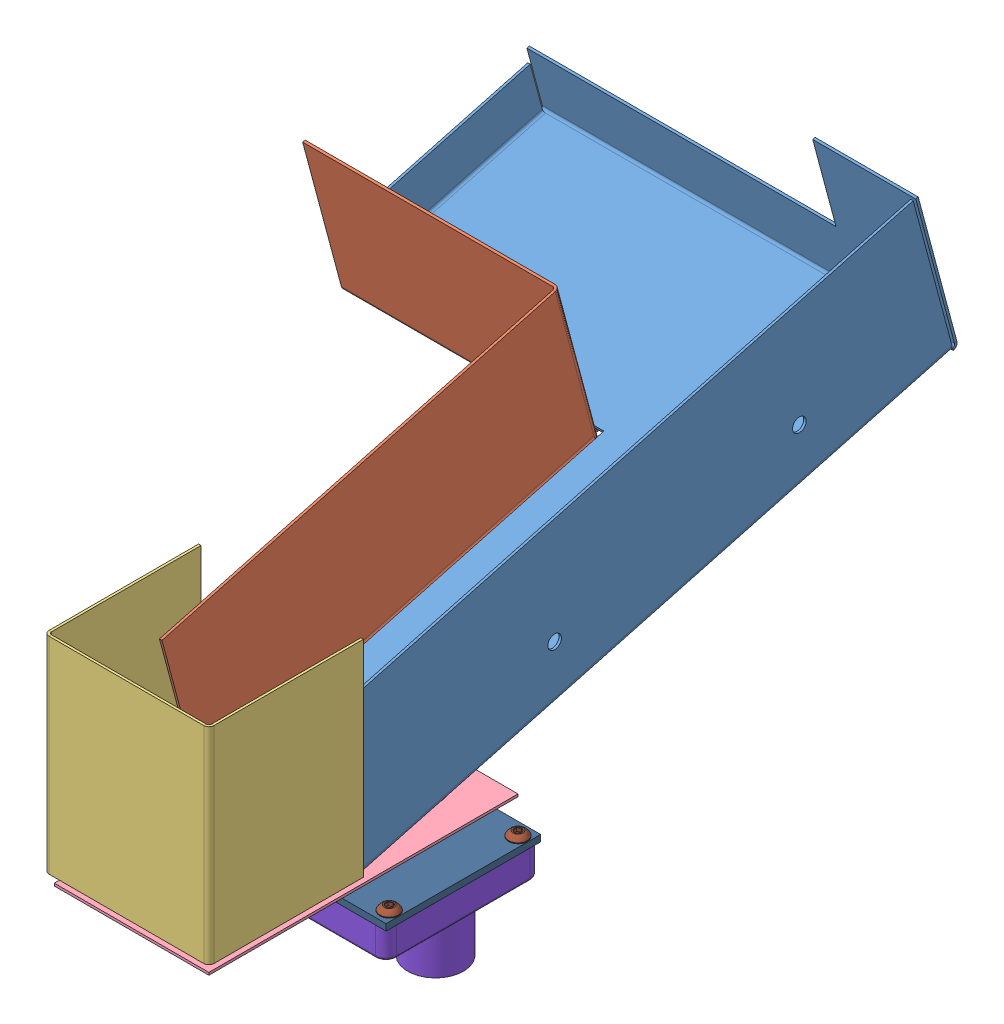
SolidWorks assembly Hopper with Dispenser Mechanism, configuration Gate + Molon Motor Assembly. Lengths in mm.
Overall size (204.42 286.03 501.24).
38 component instances, 15 part files, 56 mates.
Components (placement in the parent):
- hopper with dispenser walls-1: hopper with dispenser walls [Hopper + Dispenser Assembly] at (46.1361 -83.3926 -47.6439) size (204.42 154.24 577.12)
  - hopper-1: hopper [Hoppper Assembly] at (129.7149 -2.1881 -376.9734) x (0 -0.258819 0.965926) z (-1 0 0) size (409.96 77.67 265.99)
    - hopper start-1: hopper start [Hopper Outside Wall] at (-14.8415 81.1786 254.2257) size (304.8 76.45 203.2)
    - hopper inside-1: hopper inside [Hopper Inside Wall] at (89.2477 78.7402 254.2257) size (214.68 76.2 137.21)
  - Dispenser Walls-1: Dispenser Walls [Dispenser Wall] at (-1.3716 0 0) x (0 0 1) z (-1 0 0) size (76.2 101.6 81.28)
- Motorized Dispenser-1: Motorized Dispenser [Default] at (-167.4102 62.9008 -209.6692) x (0 0 1) z (1 0 0) size (166.69 95.97 76.2)
  - Gate-1: Gate [Gate Assembly] at (40.722 74.7431 128.7626) size (152.4 26.67 76.2)
    - Dispenser Gate-1: Dispenser Gate [Default] at (-31.0966 74.0903 164.6921) size (152.4 1.22 76.2)
    - Gate Hub-1: Gate Hub [Gate Hub] at (7.0034 95.6295 126.5921) x (0 0 -1) z (0 -1 0) size (50.8 50.8 20.32)
    - 0.25-20 Button Head Cap Screw (BHCS)-1: 0.25-20 Button Head Cap Screw (BHCS) [Default] at (-2.5216 85.0123 143.0899) x (1 0 0) z (0 -1 0) size (11.1 11.1 16.05)
    - 0.25-20 Button Head Cap Screw (BHCS)-2: 0.25-20 Button Head Cap Screw (BHCS) [Default] at (-2.5216 85.0123 110.0943) x (1 0 0) z (0 -1 0) size (11.1 11.1 16.05)
    - 0.25-20 Button Head Cap Screw (BHCS)-3: 0.25-20 Button Head Cap Screw (BHCS) [Default] at (26.0534 85.0123 126.5921) x (1 0 0) z (0 -1 0) size (11.1 11.1 16.05)
    - 80-20 0.25-20 T-NUT-1: 80-20 0.25-20 T-NUT [Default] at (-120.8742 74.0903 17.1569) x (1 0 0) z (0 -1 0) size (25.4 11.25 2.41)
    - 80-20 0.25-20 T-NUT-2: 80-20 0.25-20 T-NUT [Default] at (-120.8742 74.0903 -15.8387) x (1 0 0) z (0 -1 0) size (25.4 11.25 2.41)
    - 80-20 0.25-20 T-NUT-3: 80-20 0.25-20 T-NUT [Default] at (-99.8797 74.0903 244.9447) x (0 0 -1) z (0 -1 0) size (25.4 11.25 2.41)
  - 17.5 RPM Molon Gear Motor-1: 17.5 RPM Molon Gear Motor [Predeterminado] at (33.4378 192.2801 255.3547) x (0 0 -1) z (0 -1 0) size (69.85 76.2 87.08)
  - 3-8 Inch 0.25-20 Set Screw-1: 3-8 Inch 0.25-20 Set Screw [91375A535] at (55.3918 162.7526 255.3547) x (0 0.170115 -0.985424) z (1 0 0) size (6.35 6.35 9.71)
- Molon Mount-1: Molon Mount [Molon Motor Mount] at (122.933 -115.0918 -214.3314) x (-1 0 0) z (0 0 -1) size (122.94 3.17 76.2)
- 10-32 .75 Inch Screw-3: 10-32 .75 Inch Screw [10-32 X 0.75 in BHCS] at (57.782 -109.3514 -207.9814) x (-0.212594 0 0.977141) z (0 1 0) size (9.17 9.17 21.8)
- 10-32 .75 Inch Screw-2: 10-32 .75 Inch Screw [10-32 X 0.75 in BHCS] at (57.782 -109.3514 -144.4814) x (1 0 0) z (0 1 0) size (9.17 9.17 21.8)
- 80-20 Extrusion-5in-1: 80-20 Extrusion-5in [80-20 Extrusion - 12.0 inch] at (12.697 -127.7918 -265.1314) size (25.4 25.4 127)
- 80-20 Extrusion-2in-1: 80-20 Extrusion-2in [80-20 Extrusion - 12.0 inch] at (12.697 -216.6918 -252.4314) x (1 0 0) z (0 1 0) size (25.4 25.4 76.2)
- 10-32 .75 Inch Screw-4: 10-32 .75 Inch Screw [10-32 X 0.75 in BHCS] at (118.107 -109.3514 -207.9814) x (1 0 0) z (0 1 0) size (9.17 9.17 21.8)
- 10-32 .75 Inch Screw-5: 10-32 .75 Inch Screw [10-32 X 0.75 in BHCS] at (118.107 -109.3514 -144.4814) x (1 0 0) z (0 1 0) size (9.17 9.17 21.8)
- 80-20 0.25-20 T-NUT-1: 80-20 0.25-20 T-NUT [Default] at (-113.236 -117.327 -83.2788) x (0 0 -1) z (0 -1 0) size (25.4 11.25 2.41)
- 80-20 0.25-20 T-NUT-2: 80-20 0.25-20 T-NUT [Default] at (-113.236 -117.327 -32.4788) x (0 0 -1) z (0 -1 0) size (25.4 11.25 2.41)
- 0.25-20 Button Head Cap Screw (BHCS)-1: 0.25-20 Button Head Cap Screw (BHCS) [Default] at (12.697 -108.564 -150.8314) x (-0.837169 0 -0.546944) z (0 -1 0) size (11.1 11.1 16.05)
- 0.25-20 Button Head Cap Screw (BHCS)-2: 0.25-20 Button Head Cap Screw (BHCS) [Default] at (12.697 -108.564 -201.6314) x (0.285584 0 0.958354) z (0 -1 0) size (11.1 11.1 16.05)
- 80-20 Straight Bracket-1: 80-20 Straight Bracket [Default] at (-4.7655 -115.0918 -265.1314) x (0 0 1) z (0 1 0) size (25.4 4.76 50.8)
- 80-20 90 Degree Angle Bracket-1: 80-20 90 Degree Angle Bracket [Default] at (-0.003 -140.4918 -239.7314) x (1 0 0) z (0 -1 0) size (25.4 25.4 25.4)
- 0.25-20 Button Head Cap Screw (BHCS)-3: 0.25-20 Button Head Cap Screw (BHCS) [Default] at (-8.1183 -127.7918 -252.4314) x (0 -0.924225 -0.381849) z (1 0 0) size (11.1 11.1 16.05)
- 0.25-20 Button Head Cap Screw (BHCS)-4: 0.25-20 Button Head Cap Screw (BHCS) [Default] at (-8.1183 -153.1918 -252.4314) x (0 -0.924225 -0.381849) z (1 0 0) size (11.1 11.1 16.05)
- 0.25-20 Button Head Cap Screw (BHCS)-7: 0.25-20 Button Head Cap Screw (BHCS) [Default] at (12.697 -155.7318 -231.6161) x (-0.923728 -0.383049 0) z (0 0 -1) size (11.1 11.1 16.05)
- 0.25-20 Button Head Cap Screw (BHCS)-8: 0.25-20 Button Head Cap Screw (BHCS) [Default] at (12.697 -148.6071 -224.4914) x (1 0 0) z (0 1 0) size (11.1 11.1 16.05)
- 80-20 0.25-20 T-NUT-4: 80-20 0.25-20 T-NUT [Default] at (4.5964 -34.8393 -378.3645) x (0 -1 0) z (-1 0 0) size (25.4 11.25 2.41)
- 80-20 0.25-20 T-NUT-5: 80-20 0.25-20 T-NUT [Default] at (2.1834 -253.7249 -134.0788) x (0 0 -1) z (1 0 0) size (25.4 11.25 2.41)
- 80-20 0.25-20 T-NUT-6: 80-20 0.25-20 T-NUT [Default] at (138.6301 -138.3542 -106.1388) x (0 0 -1) z (0 1 0) size (25.4 11.25 2.41)
- 80-20 0.25-20 T-NUT-7: 80-20 0.25-20 T-NUT [Default] at (-113.236 -37.3793 -244.282) x (0 -1 0) z (0 0 1) size (25.4 11.25 2.41)
Mates (geometry in assembly coordinates):
- Distance2: distance = 2.54 mm anti-aligned: plane of hopper with dispenser walls-1/Dispenser Walls-1 through (44.7645 -83.3926 -123.8439) normal (0 -1 0); plane of Motorized Dispenser-1/Gate-1/Dispenser Gate-1 through (126.0445 -85.9326 -200.0439) normal (0 1 0)
- Coincident5: coincident aligned: plane of hopper with dispenser walls-1/Dispenser Walls-1 through (44.7645 -83.3926 -47.6439) normal (0 0 1); plane of Motorized Dispenser-1/Gate-1/Dispenser Gate-1 through (126.0445 -87.1518 -47.6439) normal (0 0 1)
- Coincident6: coincident aligned: plane of hopper with dispenser walls-1/Dispenser Walls-1 through (126.0445 -83.3926 -47.6439) normal (1 0 0); plane of Motorized Dispenser-1/Gate-1/Dispenser Gate-1 through (126.0445 -87.1518 -200.0439) normal (1 0 0)
- Coincident7: coincident anti-aligned: plane of Molon Mount-1 through (122.933 -115.0918 -214.3314) normal (0 -1 0); plane of Motorized Dispenser-1/17.5 RPM Molon Gear Motor-1 through (122.8695 -115.0918 -214.3314) normal (0 1 0)
- Concentric2: concentric aligned: cylinder of Molon Mount-1 through (118.107 -111.9168 -207.9814) axis (0 1 0) radius 2.4892; cylinder of Motorized Dispenser-1/17.5 RPM Molon Gear Motor-1 through (118.107 -115.0918 -207.9814) axis (0 1 0) radius 2.0193
- Concentric3: concentric anti-aligned: circle of Motorized Dispenser-1/17.5 RPM Molon Gear Motor-1; cylinder of 10-32 .75 Inch Screw-3 through (57.782 -130.9668 -207.9814) axis (0 -1 0) radius 2.413
- Coincident9: coincident anti-aligned: plane of Molon Mount-1 through (122.933 -111.9168 -214.3314) normal (0 1 0); plane of 10-32 .75 Inch Screw-3 through (53.3021 -111.9168 -208.9561) normal (0 -1 0)
- Concentric4: concentric anti-aligned: circle of Motorized Dispenser-1/17.5 RPM Molon Gear Motor-1; cylinder of 10-32 .75 Inch Screw-2 through (57.782 -130.9668 -144.4814) axis (0 -1 0) radius 2.413
- Coincident10: coincident anti-aligned: plane of Molon Mount-1 through (122.933 -111.9168 -214.3314) normal (0 1 0); plane of 10-32 .75 Inch Screw-2 through (57.782 -111.9168 -139.8967) normal (0 -1 0)
- Coincident21: coincident aligned: plane of Molon Mount-1 through (-0.003 -111.9168 -214.3314) normal (-1 0 0); plane of 80-20 Extrusion-5in-1 through (-0.003 -140.4918 -138.1314) normal (-1 0 0)
- Coincident22: coincident anti-aligned: plane of Molon Mount-1 through (122.933 -115.0918 -214.3314) normal (0 -1 0); plane of 80-20 Extrusion-5in-1 through (-0.003 -115.0918 -138.1314) normal (0 1 0)
- Coincident23: coincident anti-aligned: plane of 80-20 Extrusion-5in-1 through (-0.003 -140.4918 -138.1314) normal (0 -1 0); plane of 80-20 Extrusion-2in-1 through (25.397 -140.4918 -265.1314) normal (0 1 0)
- Concentric5: concentric aligned: circle of Motorized Dispenser-1/17.5 RPM Molon Gear Motor-1; circle of Molon Mount-1
- Concentric6: concentric anti-aligned: cylinder of Motorized Dispenser-1/17.5 RPM Molon Gear Motor-1 through (118.107 -115.0918 -207.9814) axis (0 1 0) radius 2.0193; cylinder of 10-32 .75 Inch Screw-4 through (118.107 -130.9668 -207.9814) axis (0 -1 0) radius 2.413
- Concentric7: concentric anti-aligned: cylinder of Motorized Dispenser-1/17.5 RPM Molon Gear Motor-1 through (118.107 -115.0918 -144.4814) axis (0 1 0) radius 2.0193; cylinder of 10-32 .75 Inch Screw-5 through (118.107 -130.9668 -144.4814) axis (0 -1 0) radius 2.413
- Coincident26: coincident anti-aligned: plane of Molon Mount-1 through (122.933 -111.9168 -214.3314) normal (0 1 0); plane of 10-32 .75 Inch Screw-4 through (118.107 -111.9168 -203.3967) normal (0 -1 0)
- Coincident27: coincident anti-aligned: plane of Molon Mount-1 through (122.933 -111.9168 -214.3314) normal (0 1 0); plane of 10-32 .75 Inch Screw-5 through (118.107 -111.9168 -139.8967) normal (0 -1 0)
- Coincident28: coincident aligned: plane of Molon Mount-1 through (-0.003 -111.9168 -138.1314) normal (0 0 1); plane of 80-20 Extrusion-5in-1 through (25.397 -115.0918 -138.1314) normal (0 0 1)
- Coincident29: coincident anti-aligned: line of 80-20 Extrusion-2in-1 through (9.0363 -140.4918 -265.1314) axis (-1 0 0); plane of 80-20 Extrusion-5in-1 through (25.397 -115.0918 -265.1314) normal (0 0 -1)
- Coincident30: coincident aligned: plane of 80-20 Extrusion-5in-1 through (-0.003 -140.4918 -138.1314) normal (-1 0 0); plane of 80-20 Extrusion-2in-1 through (-0.003 -140.4918 -239.7314) normal (-1 0 0)
- Concentric8: concentric anti-aligned: cylinder of 80-20 0.25-20 T-NUT-2 through (12.697 -117.326 -150.8314) axis (0 -1 0) radius 3.175; cylinder of 0.25-20 Button Head Cap Screw (BHCS)-1 through (12.697 -124.6168 -150.8314) axis (0 1 0) radius 3.175
- Concentric9: concentric aligned: cylinder of Molon Mount-1 through (12.697 -111.9168 -150.8314) axis (0 1 0) radius 3.3782; cylinder of 0.25-20 Button Head Cap Screw (BHCS)-1 through (12.697 -124.6168 -150.8314) axis (0 1 0) radius 3.175
- Parallel1: parallel aligned: plane of 80-20 Extrusion-5in-1 through (-0.003 -140.4918 -138.1314) normal (-1 0 0); plane of 80-20 0.25-20 T-NUT-2 through (7.0709 -119.74 -143.7575) normal (-1 0 0)
- Coincident32: coincident anti-aligned: plane of 80-20 Extrusion-5in-1 through (12.697 -117.327 -281.8705) normal (0 -1 0); plane of 80-20 0.25-20 T-NUT-2 through (12.697 -117.327 -143.7575) normal (0 1 0)
- Coincident33: coincident anti-aligned: plane of Molon Mount-1 through (122.933 -111.9168 -214.3314) normal (0 1 0); plane of 0.25-20 Button Head Cap Screw (BHCS)-1 through (8.0508 -111.9168 -153.8669) normal (0 -1 0)
- Concentric10: concentric anti-aligned: cylinder of 80-20 0.25-20 T-NUT-1 through (12.697 -117.326 -201.6314) axis (0 -1 0) radius 3.175; cylinder of 0.25-20 Button Head Cap Screw (BHCS)-2 through (12.697 -124.6168 -201.6314) axis (0 1 0) radius 3.175
- Parallel4: parallel anti-aligned: plane of 80-20 Extrusion-5in-1 through (-0.003 -140.4918 -138.1314) normal (-1 0 0); plane of 80-20 0.25-20 T-NUT-1 through (18.3231 -119.74 -194.5575) normal (1 0 0)
- Coincident35: coincident anti-aligned: plane of 80-20 Extrusion-5in-1 through (12.697 -117.327 -281.8705) normal (0 -1 0); plane of 80-20 0.25-20 T-NUT-1 through (12.697 -117.327 -194.5575) normal (0 1 0)
- Concentric14: concentric aligned: cylinder of Molon Mount-1 through (12.697 -111.9168 -201.6314) axis (0 1 0) radius 3.3782; cylinder of 0.25-20 Button Head Cap Screw (BHCS)-2 through (12.697 -124.6168 -201.6314) axis (0 1 0) radius 3.175
- Coincident36: coincident anti-aligned: plane of Molon Mount-1 through (122.933 -111.9168 -214.3314) normal (0 1 0); plane of 0.25-20 Button Head Cap Screw (BHCS)-2 through (14.282 -111.9168 -196.3126) normal (0 -1 0)
- Coincident37: coincident anti-aligned: plane of 80-20 Extrusion-2in-1 through (-0.003 -140.4918 -239.7314) normal (-1 0 0); plane of 80-20 Straight Bracket-1 through (-0.003 -115.0918 -265.1314) normal (1 0 0)
- Coincident38: coincident aligned: plane of 80-20 Extrusion-2in-1 through (-0.003 -140.4918 -265.1314) normal (0 0 -1); plane of 80-20 Straight Bracket-1 through (-0.003 -115.0918 -265.1314) normal (0 0 -1)
- Coincident39: coincident aligned: plane of 80-20 Extrusion-5in-1 through (-0.003 -115.0918 -138.1314) normal (0 1 0); plane of 80-20 Straight Bracket-1 through (-0.003 -115.0918 -265.1314) normal (0 1 0)
- Coincident43: coincident anti-aligned: plane of 80-20 Extrusion-5in-1 through (-0.003 -140.4918 -138.1314) normal (0 -1 0); plane of 80-20 90 Degree Angle Bracket-1 through (25.397 -140.4918 -214.3314) normal (0 1 0)
- Coincident44: coincident anti-aligned: plane of 80-20 Extrusion-2in-1 through (-0.003 -140.4918 -239.7314) normal (0 0 1); plane of 80-20 90 Degree Angle Bracket-1 through (25.397 -140.4918 -239.7314) normal (0 0 -1)
- Coincident45: coincident aligned: plane of 80-20 Extrusion-2in-1 through (-0.003 -140.4918 -239.7314) normal (-1 0 0); plane of 80-20 90 Degree Angle Bracket-1 through (-0.003 -161.3198 -239.5409) normal (-1 0 0)
- Concentric17: concentric aligned: cylinder of 80-20 Straight Bracket-1 through (-0.003 -127.7918 -252.4314) axis (-1 0 0) radius 3.3782; cylinder of 0.25-20 Button Head Cap Screw (BHCS)-3 through (7.9345 -127.7918 -252.4314) axis (-1 0 0) radius 3.175
- Concentric18: concentric aligned: cylinder of 80-20 Straight Bracket-1 through (-0.003 -153.1918 -252.4314) axis (-1 0 0) radius 3.3782; cylinder of 0.25-20 Button Head Cap Screw (BHCS)-4 through (7.9345 -153.1918 -252.4314) axis (-1 0 0) radius 3.175
- Coincident48: coincident anti-aligned: plane of 80-20 Straight Bracket-1 through (-4.7655 -115.0918 -265.1314) normal (-1 0 0); plane of 0.25-20 Button Head Cap Screw (BHCS)-3 through (-4.7655 -132.9212 -254.5506) normal (1 0 0)
- Coincident49: coincident anti-aligned: plane of 80-20 Straight Bracket-1 through (-4.7655 -115.0918 -265.1314) normal (-1 0 0); plane of 0.25-20 Button Head Cap Screw (BHCS)-4 through (-4.7655 -158.3212 -254.5506) normal (1 0 0)
- Concentric19: concentric anti-aligned: cylinder of 80-20 90 Degree Angle Bracket-1 through (12.697 -140.4918 -224.4914) axis (0 1 0) radius 3.2639; cylinder of 0.25-20 Button Head Cap Screw (BHCS)-8 through (12.697 -132.5543 -224.4914) axis (0 -1 0) radius 3.175
- Coincident50: coincident anti-aligned: plane of 80-20 90 Degree Angle Bracket-1 through (25.397 -145.2543 -231.7939) normal (0 -1 0); plane of 0.25-20 Button Head Cap Screw (BHCS)-8 through (18.2469 -145.2543 -224.4914) normal (0 1 0)
- Concentric20: concentric anti-aligned: cylinder of 80-20 90 Degree Angle Bracket-1 through (12.697 -155.7318 -239.7314) axis (0 0 -1) radius 3.2639; cylinder of 0.25-20 Button Head Cap Screw (BHCS)-7 through (12.697 -155.7318 -247.6689) axis (0 0 1) radius 3.175
- Coincident51: coincident anti-aligned: plane of 80-20 90 Degree Angle Bracket-1 through (25.397 -161.3198 -234.9689) normal (0 0 1); plane of 0.25-20 Button Head Cap Screw (BHCS)-7 through (7.5704 -157.8577 -234.9689) normal (0 0 -1)
- Concentric21: concentric anti-aligned: cylinder of 0.25-20 Button Head Cap Screw (BHCS)-8 through (12.697 -132.5543 -224.4914) axis (0 -1 0) radius 3.175; cylinder of 80-20 0.25-20 T-NUT-6 through (12.697 -138.3552 -224.4914) axis (0 1 0) radius 3.175
- Parallel5: parallel anti-aligned: plane of 80-20 Extrusion-5in-1 through (15.9609 -127.8894 -281.8705) normal (-1 0 0); plane of 80-20 0.25-20 T-NUT-6 through (18.3231 -135.9412 -217.4175) normal (1 0 0)
- Coincident53: coincident anti-aligned: plane of 80-20 Extrusion-5in-1 through (12.697 -138.3542 -281.8705) normal (0 1 0); plane of 80-20 0.25-20 T-NUT-6 through (12.697 -138.3542 -217.4175) normal (0 -1 0)
- Concentric22: concentric anti-aligned: cylinder of 0.25-20 Button Head Cap Screw (BHCS)-3 through (7.9345 -127.7918 -252.4314) axis (-1 0 0) radius 3.175; cylinder of 80-20 0.25-20 T-NUT-5 through (2.1824 -127.7918 -252.4314) axis (1 0 0) radius 3.175
- Parallel6: parallel aligned: plane of 80-20 Extrusion-5in-1 through (12.6482 -131.1045 -281.8705) normal (0 1 0); plane of 80-20 0.25-20 T-NUT-5 through (4.5964 -122.1657 -245.3575) normal (0 1 0)
- Coincident55: coincident anti-aligned: plane of 80-20 Extrusion-5in-1 through (2.1834 -127.8406 -281.8705) normal (1 0 0); plane of 80-20 0.25-20 T-NUT-5 through (2.1834 -127.7918 -245.3575) normal (-1 0 0)
- Coincident58: coincident anti-aligned: plane of 80-20 Extrusion-2in-1 through (2.1834 -233.431 -252.3826) normal (1 0 0); plane of 80-20 0.25-20 T-NUT-4 through (2.1834 -146.1179 -252.4314) normal (-1 0 0)
- Parallel8: parallel anti-aligned: plane of 80-20 Extrusion-2in-1 through (12.6482 -233.431 -255.6465) normal (0 0 1); plane of 80-20 0.25-20 T-NUT-4 through (2.1834 -146.1179 -258.0575) normal (0 0 -1)
- Concentric24: concentric aligned: cylinder of 0.25-20 Button Head Cap Screw (BHCS)-4 through (7.9345 -153.1918 -252.4314) axis (-1 0 0) radius 3.175; cylinder of 80-20 0.25-20 T-NUT-4 through (4.5974 -153.1918 -252.4314) axis (-1 0 0) radius 3.175
- Coincident60: coincident anti-aligned: plane of 80-20 Extrusion-2in-1 through (12.697 -233.431 -241.869) normal (0 0 -1); plane of 80-20 0.25-20 T-NUT-7 through (12.697 -148.6579 -241.869) normal (0 0 1)
- Parallel9: parallel anti-aligned: plane of 80-20 Extrusion-2in-1 through (9.4331 -233.431 -252.3338) normal (1 0 0); plane of 80-20 0.25-20 T-NUT-7 through (7.0709 -148.6579 -241.869) normal (-1 0 0)
- Concentric25: concentric aligned: cylinder of 0.25-20 Button Head Cap Screw (BHCS)-7 through (12.697 -155.7318 -247.6689) axis (0 0 1) radius 3.175; cylinder of 80-20 0.25-20 T-NUT-7 through (12.697 -155.7318 -244.283) axis (0 0 1) radius 3.175
